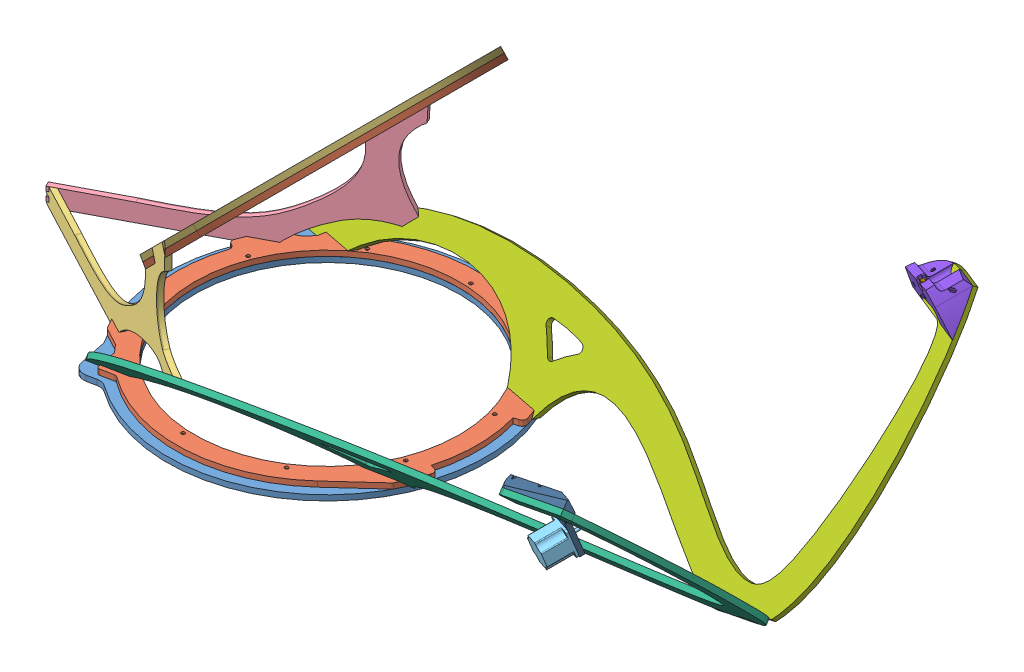
SolidWorks assembly Upper Laser cut parts, configuration Default. Lengths in mm.
Overall size (1750.38 753.76 880.02).
13 component instances, 13 part files, 32 mates.
Components (placement in the parent):
- Circular Base-1: Circular Base [Default] at (-58.9389 49.7489 -2.6974) size (711 12 711)
- Circular Base layer 2-1: Circular Base layer 2 [Default] at (-58.9389 71.7489 -2.6974) x (1 0 0) z (0 -1 0) size (674.73 670 12)
- mirror Support-1: mirror Support [Default] at (-166.9112 219.7808 256.9185) x (0.884433 0 0.466667) z (-0.466667 0 0.884433) size (686.18 345.16 12)
- mirror Support 2-1: mirror Support 2 [Default] at (-166.9112 219.7808 340.9221) x (0.884433 0 0.466667) z (-0.466667 0 0.884433) size (365.24 345.16 526.43)
- Stepper (Sparkfun 125oz)-1: Stepper (Sparkfun 125oz) [Default] at (718.0856 297.4663 334.9528) x (0.922484 0.101112 0.372558) z (-0.210467 0.940771 0.265809) size (56.4 77.1 56.4)
- Lest Side Plus Offset^Upper Laser cut parts-1: Lest Side Plus Offset^Upper Laser cut parts [Default] at (1.6148 1.9801 5.2404) x (0.999982 0.005791 0.001658) z (-0.001658 0.000068 0.999999) size (1296.04 384.36 385.05) (virtual)
- Right Side Plus Offset-1: Right Side Plus Offset [Default] at origin size (1393.16 574.9 379.93)
- Left Axel Block-1: Left Axel Block [Default] at (964.4723 573.1601 -300.5547) x (0.922484 0.101112 0.372558) z (-0.323616 -0.323616 0.889126) size (130.09 84.46 74.57)
- 608 Bearing-1: 608 Bearing [Default] at (965.9286 574.6164 -304.5558) x (0.920878 -0.323616 0.217386) z (0.217386 0.889126 0.402738) size (22 7 22)
- Right Axel Block-1: Right Axel Block [Default] at (747.6498 356.3376 295.16) x (0.922484 0.101112 0.372558) z (0.323616 0.323616 -0.889126) size (145.99 152.66 66.85)
- Secondary Mirror Front-1: Secondary Mirror Front [Default] at (-58.9389 464.7489 -2.6974) x (0 0 1) z (0.707107 0.707107 0) size (593.01 12 760)
- Secondary Mirror Back-1: Secondary Mirror Back [Default] at (-58.9389 464.7489 -2.6974) x (0 0 -1) z (0.707107 0.707107 0) size (591.82 12 760)
- Mirror-1: Mirror [Default] at (-58.9389 464.7489 -2.6974) x (-0.353553 -0.353553 -0.866025) z (-0.612372 -0.612372 0.5) size (580.26 4 669.55)
Mates (geometry in assembly coordinates):
- Coincident1: coincident anti-aligned: plane of Circular Base-1 through (-318.8421 61.7489 -251.7964) normal (0 1 0); plane of Circular Base layer 2-1 through (-58.9389 61.7489 -2.6974) normal (0 -1 0)
- Concentric1: concentric aligned: circle of Circular Base-1; circle of Circular Base layer 2-1
- Coincident6: coincident anti-aligned: plane of Circular Base layer 2-1 through (-771.4223 61.7489 -62.0487) normal (-0.466667 0 0.884433); plane of mirror Support-1 through (-337.5693 128.376 166.8717) normal (0.466667 0 -0.884433)
- Coincident7: coincident anti-aligned: plane of Circular Base layer 2-1 through (-391.4538 61.7489 222.3954) normal (-0.884433 0 -0.466667); plane of mirror Support-1 through (-361.469 71.7489 165.5678) normal (0.884433 0 0.466667)
- Coincident8: coincident anti-aligned: plane of Circular Base-1 through (-318.8421 61.7489 -251.7964) normal (0 1 0); plane of mirror Support-1 through (-680.3675 61.7489 -2.6974) normal (0 -1 0)
- Coincident10: coincident anti-aligned: plane of Circular Base-1 through (-318.8421 61.7489 -251.7964) normal (0 1 0); plane of mirror Support 2-1 through (-680.3675 61.7489 -2.6974) normal (0 -1 0)
- Coincident11: coincident anti-aligned: plane of Circular Base layer 2-1 through (-776.6399 61.7489 59.4069) normal (-0.466667 0 -0.884433); plane of mirror Support 2-1 through (-337.5693 128.376 -172.2664) normal (0.466667 0 0.884433)
- Coincident12: coincident anti-aligned: plane of Circular Base layer 2-1 through (-386.2363 61.7489 -217.9018) normal (-0.884433 0 0.466667); plane of mirror Support 2-1 through (-361.469 71.7489 -170.9625) normal (0.884433 0 -0.466667)
- Distance3: distance = 67.5 mm: line of Stepper (Sparkfun 125oz)-1 through (774.9855 298.7387 269.4115) axis (-0.323616 -0.323616 0.889126); line of Circular Base-1 through (856.0611 464.7489 -2.6974) axis (-0.323616 -0.323616 0.889126)
- Coincident40: coincident anti-aligned: plane of Right Side Plus Offset-1 through (16.9502 -61.5721 -87.201) normal (-0.156822 0.569662 0.806779); plane of assembly through (16.9502 -61.5721 -87.201) normal (0.156822 -0.569662 -0.806779)
- Concentric7: concentric anti-aligned: line of Circular Base-1 through (856.0611 464.7489 -2.6974) axis (0.323616 0.323616 -0.889126); cylinder of Left Axel Block-1 through (1048.3892 657.077 -531.1147) axis (-0.323616 -0.323616 0.889126) radius 11
- Coincident48: coincident aligned: plane of Left Axel Block-1 through (964.4723 573.1601 -300.5547) normal (-0.323616 -0.323616 0.889126); plane of assembly through (964.4723 573.1601 -300.5547) normal (-0.323616 -0.323616 0.889126)
- Concentric8: concentric anti-aligned: line of Circular Base-1 through (856.0611 464.7489 -2.6974) axis (0.323616 0.323616 -0.889126); cylinder of 608 Bearing-1 through (968.1939 576.8817 -310.7797) axis (-0.323616 -0.323616 0.889126) radius 11
- Coincident50: coincident anti-aligned: plane of Left Axel Block-1 through (965.9286 574.6164 -304.5558) normal (0.323616 0.323616 -0.889126); plane of 608 Bearing-1 through (965.9286 574.6164 -304.5558) normal (-0.323616 -0.323616 0.889126)
- Parallel6: parallel anti-aligned: plane of Lest Side Plus Offset^Upper Laser cut parts-1; plane of Left Axel Block-1
- Distance4: distance = 10 mm anti-aligned: plane of Stepper (Sparkfun 125oz)-1 through (750.7278 266.706 274.904) normal (0.323616 0.323616 -0.889126); plane of assembly through (747.6498 356.3376 295.16) normal (-0.323616 -0.323616 0.889126)
- Concentric102: concentric anti-aligned: line of Circular Base-1 through (856.0611 464.7489 -2.6974) axis (-0.323616 -0.323616 0.889126); cylinder of Right Axel Block-1 through (668.8548 277.5426 511.6476) axis (0.323616 0.323616 -0.889126) radius 11
- Coincident527: coincident anti-aligned: plane of Right Axel Block-1 through (747.6498 356.3376 295.16) normal (0.323616 0.323616 -0.889126); plane of assembly through (747.6498 356.3376 295.16) normal (-0.323616 -0.323616 0.889126)
- Parallel8: parallel: plane of Lest Side Plus Offset^Upper Laser cut parts-1; line of Right Axel Block-1 through (747.6498 356.3376 295.16) axis (-0.210467 0.940771 0.265809)
- Coincident530: coincident aligned: plane of Stepper (Sparkfun 125oz)-1 through (798.4848 271.9406 294.1914) normal (0.922484 0.101112 0.372558); plane of Right Axel Block-1 through (799.4592 267.5848 292.9607) normal (0.922484 0.101112 0.372558)
- Coincident532: coincident anti-aligned: plane of Lest Side Plus Offset^Upper Laser cut parts-1 through (12.1967 -52.2663 59.6798) normal (-0.136405 0.699252 -0.701741); plane of assembly through (10.9247 -56.0037 56.203) normal (0.136405 -0.699252 0.701741)
- Coincident536: coincident: point of Circular Base-1; point of Lest Side Plus Offset^Upper Laser cut parts-1
- Coincident537: coincident: point of Circular Base-1; point of Secondary Mirror Front-1
- Coincident539: coincident: plane of Circular Base-1 through (-266.4389 257.2489 -2.6974) normal (0.707107 -0.707107 0); line of Secondary Mirror Front-1 through (-426.825 96.8628 -2.6974) axis (0.707107 0.707107 0)
- Coincident542: coincident anti-aligned: plane of Circular Base-1 through (-266.4389 257.2489 -2.6974) normal (0.707107 -0.707107 0); plane of Secondary Mirror Front-1 through (-58.9389 464.7489 -2.6974) normal (-0.707107 0.707107 0)
- Coincident543: coincident: point of Circular Base-1; line of Secondary Mirror Front-1 through (-426.825 96.8628 -2.6974) axis (0.707107 0.707107 0)
- Coincident544: coincident: point of Secondary Mirror Front-1; point of Secondary Mirror Back-1
- Coincident545: coincident anti-aligned: plane of Secondary Mirror Front-1 through (-58.9389 464.7489 -2.6974) normal (-0.707107 0.707107 0); plane of Secondary Mirror Back-1 through (-58.9389 464.7489 -2.6974) normal (0.707107 -0.707107 0)
- Coincident546: coincident: point of Secondary Mirror Front-1; point of Secondary Mirror Back-1
- Coincident547: coincident anti-aligned: plane of Secondary Mirror Back-1 through (-58.9389 464.7489 -2.6974) normal (0.707107 -0.707107 0); plane of Mirror-1 through (-58.9389 464.7489 -2.6974) normal (-0.707107 0.707107 0)
- Coincident549: coincident: point of Secondary Mirror Back-1; point of Mirror-1
- Coincident551: coincident: point of Secondary Mirror Back-1; line of Mirror-1 through (-58.9389 464.7489 -2.6974) axis (0.707107 0.707107 0)
